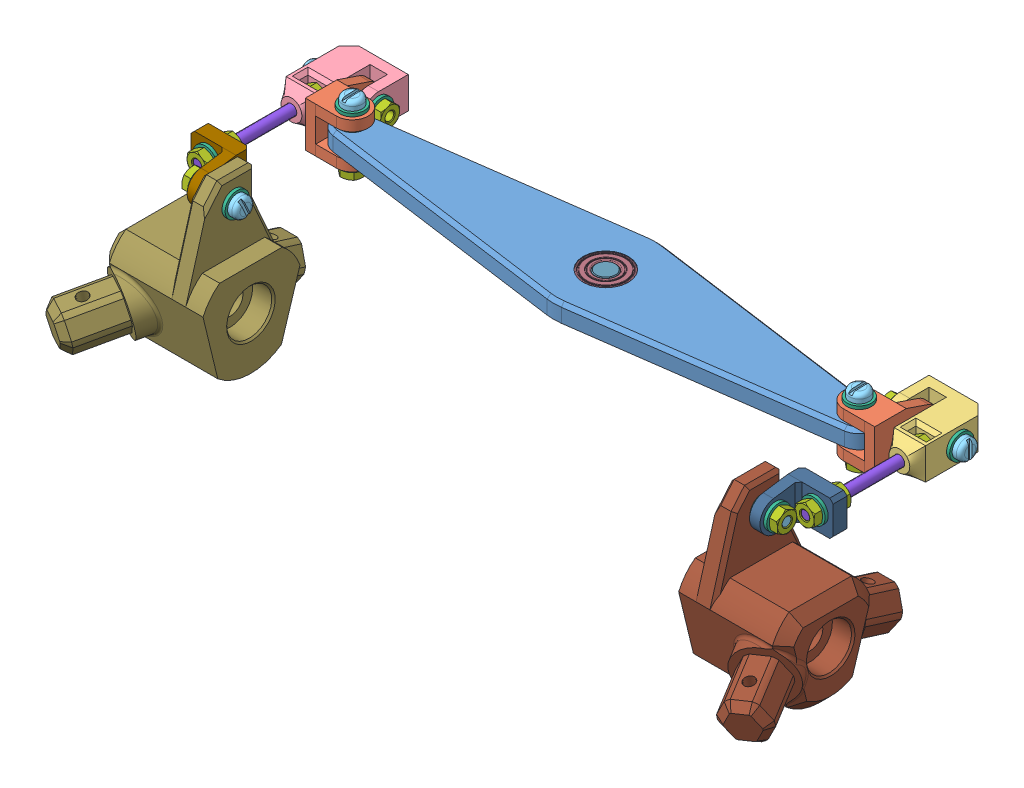
SolidWorks assembly diff-sub, configuration Default. Lengths in mm.
Overall size (208.29 64.87 81.95).
58 component instances, 14 part files, 67 mates.
Components (placement in the parent):
- diffSub-1: diffSub [Default] at (64.4054 0.5212 -28.8254) x (0 0 1) z (-1 0 0) size (33.11 19.68 190.97) (flexible)
  - differentialBar-1: differentialBar [Default] at (-60.7169 0 132.4054) x (1 0 0) z (0 1 0) size (30 156 5)
  - differentialHinge-1: differentialHinge [Default] at (109.2895 6 -3.7047) x (-0.999999 0 0.001295) z (0 1 0) size (18.65 13.57 13)
  - rodHinge-diff-left-1: rodHinge-diff-left [Default] at (109.2895 0 -2.6005) size (21.11 9.1 17.1)
  - rodHinge-diff-right-1: rodHinge-diff-right [Default] at (109.2895 0 147.4113) x (1 0 0) z (0 0 1) size (21.11 9.1 17.1)
  - differentialHinge-2: differentialHinge [Default] at (109.2895 -1 132.5155) x (-0.999999 0 -0.001295) z (0 -1 0) size (18.65 13.57 13)
  - pan slot head_am-1: pan slot head_am [B18.6.7M - M3 x 0.5 x 16 Slotted PHMS --16C] at (24.2831 12.3 137.4054) x (0 -1 0) z (0.999132 0 -0.041653) size (18.48 5.6 5.6)
  - flat washer narrow_am-1: flat washer narrow_am [B18.22M - Plain washer, 3 mm, narrow] at (24.2831 -4 137.4054) x (0 1 0) z (0.996885 0 -0.078866) size (0.9 7 7)
  - flat washer narrow_am-2: flat washer narrow_am [B18.22M - Plain washer, 3 mm, narrow] at (24.2831 -0.1 137.4054) x (0 1 0) z (0.98651 0 -0.163698) size (0.9 7 7)
  - flat washer narrow_am-3: flat washer narrow_am [B18.22M - Plain washer, 3 mm, narrow] at (24.2831 6 137.4054) x (0 1 0) z (1 0 0) size (0.9 7 7)
  - flat washer narrow_am-4: flat washer narrow_am [B18.22M - Plain washer, 3 mm, narrow] at (24.2831 9 137.4054) x (0 -1 0) z (1 0 0) size (0.9 7 7)
  - hex nut style 1_am-1: hex nut style 1_am [B18.2.4.1M - Hex nut, Style 1,  M3 x 0.5 --D-C] at (24.2831 -7.3 137.4054) x (0.148724 0 -0.988879) z (0 -1 0) size (5.5 6.35 2.4)
  - pan slot head_am-2: pan slot head_am [B18.6.7M - M3 x 0.5 x 16 Slotted PHMS --16C] at (24.2831 12.3 -8.5946) x (0 -1 0) z (0.999132 0 -0.041653) size (18.48 5.6 5.6)
  - flat washer narrow_am-5: flat washer narrow_am [B18.22M - Plain washer, 3 mm, narrow] at (24.2831 -4 -8.5946) x (0 1 0) z (0.996885 0 -0.078866) size (0.9 7 7)
  - flat washer narrow_am-6: flat washer narrow_am [B18.22M - Plain washer, 3 mm, narrow] at (24.2831 -0.1 -8.5946) x (0 1 0) z (0.98651 0 -0.163698) size (0.9 7 7)
  - flat washer narrow_am-7: flat washer narrow_am [B18.22M - Plain washer, 3 mm, narrow] at (24.2831 6 -8.5946) x (0 1 0) z (1 0 0) size (0.9 7 7)
  - flat washer narrow_am-8: flat washer narrow_am [B18.22M - Plain washer, 3 mm, narrow] at (24.2831 9 -8.5946) x (0 -1 0) z (1 0 0) size (0.9 7 7)
  - hex nut style 1_am-2: hex nut style 1_am [B18.2.4.1M - Hex nut, Style 1,  M3 x 0.5 --D-C] at (24.2831 -7.3 -8.5946) x (0.148724 0 -0.988879) z (0 -1 0) size (5.5 6.35 2.4)
  - pan slot head_am-3: pan slot head_am [B18.6.7M - M3 x 0.5 x 16 Slotted PHMS --16C] at (14.7253 2.5 159.8113) x (0 0 -1) z (-0.387279 0.921963 0) size (18.48 5.6 5.6)
  - flat washer narrow_am-9: flat washer narrow_am [B18.22M - Plain washer, 3 mm, narrow] at (14.7253 2.5 139.4113) x (0 0 1) z (0.421376 -0.906886 0) size (0.9 7 7)
  - flat washer narrow_am-10: flat washer narrow_am [B18.22M - Plain washer, 3 mm, narrow] at (14.7253 2.5 143.3113) x (0 0 1) z (-0.497272 0.867595 0) size (0.9 7 7)
  - flat washer narrow_am-11: flat washer narrow_am [B18.22M - Plain washer, 3 mm, narrow] at (14.7253 2.5 147.4113) x (0 0 1) z (-0.34854 0.937294 0) size (0.9 7 7)
  - flat washer narrow_am-12: flat washer narrow_am [B18.22M - Plain washer, 3 mm, narrow] at (14.7253 2.5 156.5113) x (0 0 -1) z (0.34854 -0.937294 0) size (0.9 7 7)
  - hex nut style 1_am-3: hex nut style 1_am [B18.2.4.1M - Hex nut, Style 1,  M3 x 0.5 --D-C] at (14.7253 2.5 136.1113) x (-0.978706 -0.205266 0) z (0 0 -1) size (5.5 6.35 2.4)
  - pan slot head_am-4: pan slot head_am [B18.6.7M - M3 x 0.5 x 16 Slotted PHMS --16C] at (14.7253 2.5 -31.0005) x (0 0 1) z (-0.009376 0.999956 0) size (18.48 5.6 5.6)
  - flat washer narrow_am-13: flat washer narrow_am [B18.22M - Plain washer, 3 mm, narrow] at (14.7253 2.5 -10.6005) x (0 0 -1) z (0.027903 0.999611 0) size (0.9 7 7)
  - flat washer narrow_am-14: flat washer narrow_am [B18.22M - Plain washer, 3 mm, narrow] at (14.7253 2.5 -14.5005) x (0 0 -1) z (0.113154 0.993577 0) size (0.9 7 7)
  - flat washer narrow_am-15: flat washer narrow_am [B18.22M - Plain washer, 3 mm, narrow] at (14.7253 2.5 -18.6005) x (0 0 -1) z (-0.051019 0.998698 0) size (0.9 7 7)
  - flat washer narrow_am-16: flat washer narrow_am [B18.22M - Plain washer, 3 mm, narrow] at (14.7253 2.5 -27.7005) x (0 0 1) z (-0.051019 0.998698 0) size (0.9 7 7)
  - hex nut style 1_am-4: hex nut style 1_am [B18.2.4.1M - Hex nut, Style 1,  M3 x 0.5 --D-C] at (14.7253 2.5 -7.3005) x (0.980003 0.198982 0) z (0 0 1) size (5.5 6.35 2.4)
  - hex nut style 1_am-5: hex nut style 1_am [B18.2.4.1M - Hex nut, Style 1,  M3 x 0.5 --D-C] at (22.1753 2.5 -23.1505) x (0 0 -1) z (1 0 0) size (5.5 6.35 2.4)
  - hex nut style 1_am-6: hex nut style 1_am [B18.2.4.1M - Hex nut, Style 1,  M3 x 0.5 --D-C] at (22.1753 2.5 151.9613) x (0 0 -1) z (1 0 0) size (5.5 6.35 2.4)
- rod^diff-sub-1: rod^diff-sub [Default] at (67.0268 0.3546 -1.55) x (0.999967 0.008111 0) z (0 0 1) size (3 3 36) (virtual)
- rod^diff-sub-2: rod^diff-sub [Default] at (-108.0952 0.4346 -1.55) x (0.999991 0.004212 0) z (0 0 1) size (3 3 36) (virtual)
- rodHinge-sus-1: rodHinge-sus [Default] at (-79.5 -22.8365 29.1809) x (0 0.297904 0.954596) z (-1 0 0) size (15.98 12.99 13)
- rodHinge-sus-left-1: rodHinge-sus-left [Default] at (79.5 -22.8365 29.1809) x (0 0.297904 0.954596) z (-1 0 0) size (15.98 12.99 13)
- flat washer narrow_am-1: flat washer narrow_am [B18.22M - Plain washer, 3 mm, narrow] at (-87.5559 3.0212 18.45) x (0 0 1) z (-0.343181 -0.939269 0) size (0.9 7 7)
- flat washer narrow_am-2: flat washer narrow_am [B18.22M - Plain washer, 3 mm, narrow] at (-87.5559 3.0212 23.35) x (0 0 1) z (-0.343181 -0.939269 0) size (0.9 7 7)
- hex nut style 1_am-1: hex nut style 1_am [B18.2.4.1M - Hex nut, Style 1,  M3 x 0.5 --D-C] at (-87.5559 3.0212 17.55) x (0.999991 0.004212 0) z (0 0 1) size (5.5 6.35 2.4)
- hex nut style 1_am-2: hex nut style 1_am [B18.2.4.1M - Hex nut, Style 1,  M3 x 0.5 --D-C] at (-87.5559 3.0212 25.75) x (0.999991 0.004212 0) z (0 0 1) size (5.5 6.35 2.4)
- flat washer narrow_am-5: flat washer narrow_am [B18.22M - Plain washer, 3 mm, narrow] at (87.5559 3.0212 18.45) x (0 0 1) z (-0.339516 -0.9406 0) size (0.9 7 7)
- hex nut style 1_am-5: hex nut style 1_am [B18.2.4.1M - Hex nut, Style 1,  M3 x 0.5 --D-C] at (87.5559 3.0212 17.55) x (0.999967 0.008111 0) z (0 0 1) size (5.5 6.35 2.4)
- hex nut style 1_am-6: hex nut style 1_am [B18.2.4.1M - Hex nut, Style 1,  M3 x 0.5 --D-C] at (87.5559 3.0212 25.75) x (0.999967 0.008111 0) z (0 0 1) size (5.5 6.35 2.4)
- flat washer narrow_am-6: flat washer narrow_am [B18.22M - Plain washer, 3 mm, narrow] at (87.5559 3.0212 23.35) x (0 0 1) z (-0.339516 -0.9406 0) size (0.9 7 7)
- rockerJoint-left-1: rockerJoint-left [Default] at (68.5 -22.8365 29.1809) x (-1 0 0) z (0 -0.297904 -0.954596) size (35.64 50.55 55.79)
- rockerJoint-right-1: rockerJoint-right [Default] at (-68.5 -22.8365 29.1809) x (-1 0 0) z (0 -0.297904 -0.954596) size (35.64 50.55 55.79)
- 6x13x5BearingShielded-1: 6x13x5BearingShielded [Default] at (0 0.5212 -4.5422) size (13 5 13)
- shaft^diff-sub-1: shaft^diff-sub [Default] at (-68 5.5212 -89.5422) x (0 0 1) z (0 1 0) size (6 6 15) (virtual)
- pan slot head_am-1: pan slot head_am [B18.6.7M - M3 x 0.5 x 13 Slotted PHMS --13C] at (-70.2 2.1635 29) x (-1 0 0) z (0 -0.907517 -0.420015) size (15.4 5.6 5.6)
- flat washer narrow_am-7: flat washer narrow_am [B18.22M - Plain washer, 3 mm, narrow] at (-83.4 2.1635 29) x (-1 0 0) z (0 -0.906886 0.421376) size (0.9 7 7)
- flat washer narrow_am-8: flat washer narrow_am [B18.22M - Plain washer, 3 mm, narrow] at (-79.5 2.1635 29) x (-1 0 0) z (0 -0.906886 0.421376) size (0.9 7 7)
- flat washer narrow_am-9: flat washer narrow_am [B18.22M - Plain washer, 3 mm, narrow] at (-73.5 2.1635 29) x (-1 0 0) z (0 -0.906886 0.421376) size (0.9 7 7)
- hex nut style 1_am-7: hex nut style 1_am [B18.2.4.1M - Hex nut, Style 1,  M3 x 0.5 --D-C] at (-83.4 2.1635 29) x (0 -0.205266 -0.978706) z (1 0 0) size (5.5 6.35 2.4)
- pan slot head_am-2: pan slot head_am [B18.6.7M - M3 x 0.5 x 13 Slotted PHMS --13C] at (70.2 2.1635 29) x (1 0 0) z (0 0.041653 0.999132) size (15.4 5.6 5.6)
- flat washer narrow_am-10: flat washer narrow_am [B18.22M - Plain washer, 3 mm, narrow] at (83.4 2.1635 29) x (1 0 0) z (0 -0.73574 0.677265) size (0.9 7 7)
- flat washer narrow_am-11: flat washer narrow_am [B18.22M - Plain washer, 3 mm, narrow] at (79.5 2.1635 29) x (1 0 0) z (0 -0.73574 0.677265) size (0.9 7 7)
- flat washer narrow_am-12: flat washer narrow_am [B18.22M - Plain washer, 3 mm, narrow] at (73.5 2.1635 29) x (1 0 0) z (0 0.73574 -0.677265) size (0.9 7 7)
- hex nut style 1_am-8: hex nut style 1_am [B18.2.4.1M - Hex nut, Style 1,  M3 x 0.5 --D-C] at (83.4 2.1635 29) x (0 -0.826163 -0.563431) z (-1 0 0) size (5.5 6.35 2.4)
Mates (geometry in assembly coordinates):
- Concentric1: concentric aligned: cylinder of diffSub-1/rodHinge-diff-left-1 through (87.5559 3.0212 -26.651) axis (0 0 1) radius 1.55; cylinder of rod^diff-sub-1 through (87.5559 3.0212 -10.55) axis (0 0 1) radius 1.5
- Tangent1: tangent anti-aligned: cylinder of diffSub-1/rodHinge-diff-left-1 through (92.1059 3.0212 -14.1) axis (-1 0 0) radius 3.55; plane of rod^diff-sub-1 through (87.5559 3.0212 -10.55) normal (0 0 -1)
- Concentric2: concentric aligned: cylinder of diffSub-1/rodHinge-diff-right-1 through (-87.5559 3.0212 -26.651) axis (0 0 1) radius 1.55; cylinder of rod^diff-sub-2 through (-87.5559 3.0212 -10.55) axis (0 0 1) radius 1.5
- Tangent2: tangent anti-aligned: cylinder of diffSub-1/rodHinge-diff-right-1 through (-92.1059 3.0212 -14.1) axis (1 0 0) radius 3.55; plane of rod^diff-sub-2 through (-87.5559 3.0212 -10.55) normal (0 0 -1)
- Tangent3: tangent: cylinder of diffSub-1/rodHinge-diff-right-1 through (-87.5559 3.0212 -26.651) axis (0 0 1) radius 1.55; face of rodHinge-sus-1
- Parallel4: parallel anti-aligned: cylinder of rod^diff-sub-2 through (-87.5559 3.0212 -10.55) axis (0 0 1) radius 1.5; face of rodHinge-sus-1
- Distance1: distance = 20 mm anti-aligned: plane of rodHinge-sus-1 through (-82.5 -22.8365 18.45) normal (0 0 -1); plane of diffSub-1/rodHinge-diff-right-1 through (-87.5559 3.0212 -1.55) normal (0 0 1)
- Concentric3: concentric aligned: cylinder of rod^diff-sub-2 through (-87.5559 3.0212 -10.55) axis (0 0 1) radius 1.5; cylinder of hex nut style 1_am-1 through (-87.5559 3.0212 15.15) axis (0 0 1) radius 1.25
- Concentric4: concentric aligned: cylinder of rod^diff-sub-2 through (-87.5559 3.0212 -10.55) axis (0 0 1) radius 1.5; cylinder of hex nut style 1_am-2 through (-87.5559 3.0212 23.35) axis (0 0 1) radius 1.25
- Concentric5: concentric anti-aligned: cylinder of rod^diff-sub-2 through (-87.5559 3.0212 -10.55) axis (0 0 1) radius 1.5; cylinder of flat washer narrow_am-2 through (-87.5559 3.0212 -11.575) axis (0 0 -1) radius 1.84
- Concentric6: concentric anti-aligned: cylinder of rod^diff-sub-2 through (-87.5559 3.0212 -10.55) axis (0 0 1) radius 1.5; cylinder of flat washer narrow_am-1 through (-87.5559 3.0212 -16.475) axis (0 0 -1) radius 1.84
- Coincident5: coincident anti-aligned: plane of rodHinge-sus-1 through (-82.5 -22.8365 18.45) normal (0 0 -1); plane of flat washer narrow_am-1 through (-89.2841 3.6526 18.45) normal (0 0 1)
- Coincident6: coincident anti-aligned: plane of rodHinge-sus-1 through (-92.5 -2.3865 22.45) normal (0 0 1); plane of flat washer narrow_am-2 through (-90.8433 4.2223 22.45) normal (0 0 -1)
- Coincident7: coincident anti-aligned: plane of flat washer narrow_am-2 through (-89.2841 3.6526 23.35) normal (0 0 1); plane of hex nut style 1_am-2 through (-87.5693 6.1966 23.35) normal (0 0 -1)
- Coincident8: coincident anti-aligned: plane of flat washer narrow_am-1 through (-90.8433 4.2223 17.55) normal (0 0 -1); plane of hex nut style 1_am-1 through (-87.5693 6.1966 17.55) normal (0 0 1)
- Tangent4: tangent: cylinder of diffSub-1/rodHinge-diff-left-1 through (87.5559 3.0212 -26.651) axis (0 0 1) radius 1.55; face of rodHinge-sus-left-1
- Parallel6: parallel anti-aligned: cylinder of rod^diff-sub-1 through (87.5559 3.0212 -10.55) axis (0 0 1) radius 1.5; face of rodHinge-sus-left-1
- Distance2: distance = 20 mm anti-aligned: plane of rodHinge-sus-left-1 through (82.5 -22.8365 18.45) normal (0 0 -1); plane of diffSub-1/rodHinge-diff-left-1 through (87.5559 3.0212 -1.55) normal (0 0 1)
- Coincident12: coincident anti-aligned: plane of hex nut style 1_am-6 through (87.5301 6.1965 23.35) normal (0 0 -1); plane of flat washer narrow_am-6 through (85.8252 3.6459 23.35) normal (0 0 1)
- Coincident13: coincident anti-aligned: plane of flat washer narrow_am-5 through (84.2638 4.2095 17.55) normal (0 0 -1); plane of hex nut style 1_am-5 through (87.5301 6.1965 17.55) normal (0 0 1)
- Concentric8: concentric aligned: cylinder of rod^diff-sub-1 through (87.5559 3.0212 -10.55) axis (0 0 1) radius 1.5; cylinder of hex nut style 1_am-5 through (87.5559 3.0212 15.15) axis (0 0 1) radius 1.25
- Concentric9: concentric aligned: cylinder of rod^diff-sub-1 through (87.5559 3.0212 -10.55) axis (0 0 1) radius 1.5; cylinder of hex nut style 1_am-6 through (87.5559 3.0212 23.35) axis (0 0 1) radius 1.25
- Concentric10: concentric anti-aligned: cylinder of rod^diff-sub-1 through (87.5559 3.0212 -10.55) axis (0 0 1) radius 1.5; cylinder of flat washer narrow_am-6 through (87.5559 3.0212 -11.575) axis (0 0 -1) radius 1.84
- Concentric11: concentric anti-aligned: cylinder of rod^diff-sub-1 through (87.5559 3.0212 -10.55) axis (0 0 1) radius 1.5; cylinder of flat washer narrow_am-5 through (87.5559 3.0212 -16.475) axis (0 0 -1) radius 1.84
- Coincident14: coincident anti-aligned: plane of rodHinge-sus-left-1 through (82.5 -22.8365 18.45) normal (0 0 -1); plane of flat washer narrow_am-5 through (85.8252 3.6459 18.45) normal (0 0 1)
- Coincident15: coincident anti-aligned: plane of rodHinge-sus-left-1 through (92.5 -2.3865 22.45) normal (0 0 1); plane of flat washer narrow_am-6 through (84.2638 4.2095 22.45) normal (0 0 -1)
- Concentric13: concentric anti-aligned: cylinder of rodHinge-sus-left-1 through (82.5 2.1635 29) axis (-1 0 0) radius 1.55; cylinder of rockerJoint-left-1 through (68.499 2.1635 29) axis (1 0 0) radius 1.55
- Distance3: distance = 1 mm anti-aligned: plane of rockerJoint-left-1 through (78.5 -16.9186 15.0358) normal (1 0 0); plane of rodHinge-sus-left-1 through (79.5 -22.8365 29.1809) normal (-1 0 0)
- Concentric14: concentric anti-aligned: cylinder of rodHinge-sus-1 through (-82.5 2.1635 29) axis (1 0 0) radius 1.55; cylinder of rockerJoint-right-1 through (-68.499 2.1635 29) axis (-1 0 0) radius 1.55
- Distance4: distance = 1 mm anti-aligned: plane of rockerJoint-right-1 through (-78.5 -16.9186 15.0358) normal (-1 0 0); plane of rodHinge-sus-1 through (-79.5 -22.8365 29.1809) normal (1 0 0)
- Coincident18: coincident aligned: plane of rockerJoint-left-1 through (98.501 -10.8365 29.1809) normal (0 1 0); plane of rockerJoint-right-1 through (-98.501 -10.8365 29.1809) normal (0 1 0)
- Parallel9: parallel aligned: plane of rockerJoint-left-1 through (98.501 -10.8365 29.1809) normal (0 1 0); plane of assembly through (0 0 0) normal (0 1 0)
- Coincident22: coincident anti-aligned: plane of diffSub-1/differentialBar-1; plane of assembly through (0 0 0) normal (1 0 0)
- Coincident25: coincident aligned: plane of diffSub-1/differentialHinge-1 through (82.0059 6.5212 0) normal (0 0 1); plane of assembly through (0 0 0) normal (0 0 1)
- Coincident26: coincident anti-aligned: plane of diffSub-1/differentialBar-1; plane of assembly through (0 0 0) normal (1 0 0)
- Coincident27: coincident aligned: plane of diffSub-1/differentialHinge-2 through (-82.0059 -0.4788 0) normal (0 0 1); plane of assembly through (0 0 0) normal (0 0 1)
- Parallel17: parallel anti-aligned: plane of diffSub-1/rodHinge-diff-left-1 through (83.0059 0.5212 -22.65) normal (0 0 -1); plane of assembly through (0 0 0) normal (0 0 1)
- Parallel18: parallel aligned: plane of diffSub-1/rodHinge-diff-left-1 through (92.1059 0.5212 80.4642) normal (1 0 0); plane of rodHinge-sus-left-1 through (92.5 -22.8365 29.1809) normal (1 0 0)
- Parallel19: parallel aligned: plane of diffSub-1/rodHinge-diff-right-1 through (-92.1059 0.5212 80.4642) normal (-1 0 0); plane of rodHinge-sus-1 through (-92.5 -22.8365 29.1809) normal (-1 0 0)
- Parallel20: parallel aligned: plane of diffSub-1/differentialBar-1 through (-68 5.5212 -89.5422) normal (0 1 0); plane of assembly through (0 0 0) normal (0 1 0)
- Parallel21: parallel aligned: plane of rockerJoint-left-1 through (98.501 -10.8365 29.1809) normal (0 1 0); plane of assembly through (0 0 0) normal (0 1 0)
- Concentric15: concentric aligned: cylinder of diffSub-1/differentialBar-1 through (0 5.5222 -4.5422) axis (0 -1 0) radius 6.5; cylinder of 6x13x5BearingShielded-1 through (0 5.5212 -4.5422) axis (0 -1 0) radius 6.5
- Coincident28: coincident aligned: plane of diffSub-1/differentialBar-1 through (-68 5.5212 -89.5422) normal (0 1 0); plane of 6x13x5BearingShielded-1 through (0 5.5212 -4.5422) normal (0 1 0)
- InPlace1: in place: plane of diffSub-1/differentialBar-1 through (-68 5.5212 -89.5422) normal (0 1 0); plane of ? through (0 5.5212 0) normal (0 1 0); moOrthogonalPlaneRef_w of diffSub-1/differentialBar-1 through (-68 5.5212 -89.5422) normal (0 1 0); plane of ? through (0 5.5212 0) normal (0 0 -1); plane of diffSub-1/differentialBar-1 through (-68 5.5212 -89.5422) normal (0 1 0); unknown of ?; plane of diffSub-1/differentialBar-1 through (-68 5.5212 -89.5422) normal (0 1 0); unknown of shaft^diff-sub-1
- Coincident29: coincident aligned: plane of diffSub-1/differentialBar-1; plane of shaft^diff-sub-1
- Coincident30: coincident aligned: moOrthogonalPlaneRef_w of diffSub-1/differentialBar-1 through (-68 5.5212 -89.5422) normal (1 0 0); plane of shaft^diff-sub-1
- Coincident31: coincident anti-aligned: moOrthogonalPlaneRef_w of diffSub-1/differentialBar-1 through (-68 5.5212 -89.5422) normal (0 0 -1); plane of shaft^diff-sub-1
- Concentric16: concentric aligned: cylinder of rodHinge-sus-1 through (-82.5 2.1635 29) axis (1 0 0) radius 1.55; cylinder of pan slot head_am-1 through (-44.8 2.1635 29) axis (1 0 0) radius 1.5
- Concentric17: concentric aligned: cylinder of pan slot head_am-1 through (-44.8 2.1635 29) axis (1 0 0) radius 1.5; cylinder of flat washer narrow_am-7 through (-48.475 2.1635 29) axis (1 0 0) radius 1.84
- Concentric18: concentric aligned: cylinder of pan slot head_am-1 through (-44.8 2.1635 29) axis (1 0 0) radius 1.5; cylinder of flat washer narrow_am-8 through (-44.575 2.1635 29) axis (1 0 0) radius 1.84
- Concentric19: concentric aligned: cylinder of pan slot head_am-1 through (-44.8 2.1635 29) axis (1 0 0) radius 1.5; cylinder of flat washer narrow_am-9 through (-38.575 2.1635 29) axis (1 0 0) radius 1.84
- Concentric20: concentric aligned: cylinder of pan slot head_am-1 through (-44.8 2.1635 29) axis (1 0 0) radius 1.5; cylinder of hex nut style 1_am-7 through (-85.8 2.1635 29) axis (1 0 0) radius 1.25
- Coincident32: coincident anti-aligned: plane of pan slot head_am-1 through (-72.6 2.7935 27.6387) normal (-1 0 0); plane of flat washer narrow_am-9 through (-72.6 0.6886 25.8259) normal (1 0 0)
- Coincident33: coincident anti-aligned: plane of rockerJoint-right-1 through (-73.5 -16.9186 42.9642) normal (1 0 0); plane of flat washer narrow_am-9 through (-73.5 1.3881 27.3313) normal (-1 0 0)
- Coincident34: coincident anti-aligned: plane of rodHinge-sus-1 through (-79.5 -22.8365 29.1809) normal (1 0 0); plane of flat washer narrow_am-8 through (-79.5 1.3881 27.3313) normal (-1 0 0)
- Coincident35: coincident anti-aligned: plane of rodHinge-sus-1 through (-82.5 -22.8365 29.1809) normal (-1 0 0); plane of flat washer narrow_am-7 through (-82.5 0.6886 25.8259) normal (1 0 0)
- Coincident36: coincident anti-aligned: plane of flat washer narrow_am-7 through (-83.4 1.3881 27.3313) normal (-1 0 0); plane of hex nut style 1_am-7 through (-83.4 5.2713 28.3482) normal (1 0 0)
- Concentric21: concentric aligned: cylinder of pan slot head_am-2 through (44.8 2.1635 29) axis (-1 0 0) radius 1.5; cylinder of flat washer narrow_am-10 through (48.475 2.1635 29) axis (-1 0 0) radius 1.84
- Concentric22: concentric aligned: cylinder of pan slot head_am-2 through (44.8 2.1635 29) axis (-1 0 0) radius 1.5; cylinder of flat washer narrow_am-11 through (44.575 2.1635 29) axis (-1 0 0) radius 1.84
- Concentric23: concentric aligned: cylinder of pan slot head_am-2 through (44.8 2.1635 29) axis (-1 0 0) radius 1.5; cylinder of flat washer narrow_am-12 through (38.575 2.1635 29) axis (-1 0 0) radius 1.84
- Concentric24: concentric aligned: cylinder of pan slot head_am-2 through (44.8 2.1635 29) axis (-1 0 0) radius 1.5; cylinder of hex nut style 1_am-8 through (85.8 2.1635 29) axis (-1 0 0) radius 1.25
- Coincident37: coincident anti-aligned: plane of pan slot head_am-2 through (72.6 3.6622 28.9375) normal (1 0 0); plane of flat washer narrow_am-12 through (72.6 -0.207 26.4249) normal (-1 0 0)
- Coincident38: coincident anti-aligned: plane of flat washer narrow_am-10 through (83.4 3.4096 30.3538) normal (1 0 0); plane of hex nut style 1_am-8 through (83.4 0.3743 31.6234) normal (-1 0 0)
- Concentric25: concentric aligned: cylinder of rodHinge-sus-left-1 through (82.5 2.1635 29) axis (-1 0 0) radius 1.55; cylinder of pan slot head_am-2 through (44.8 2.1635 29) axis (-1 0 0) radius 1.5
- Coincident39: coincident anti-aligned: plane of rockerJoint-left-1 through (73.5 -16.9186 42.9642) normal (-1 0 0); plane of flat washer narrow_am-12 through (73.5 0.9173 27.6462) normal (1 0 0)
- Coincident40: coincident anti-aligned: plane of rodHinge-sus-left-1 through (79.5 -22.8365 29.1809) normal (-1 0 0); plane of flat washer narrow_am-11 through (79.5 3.4096 30.3538) normal (1 0 0)
- Coincident41: coincident anti-aligned: plane of rodHinge-sus-left-1 through (82.5 -22.8365 29.1809) normal (1 0 0); plane of flat washer narrow_am-10 through (82.5 4.5339 31.5751) normal (-1 0 0)
